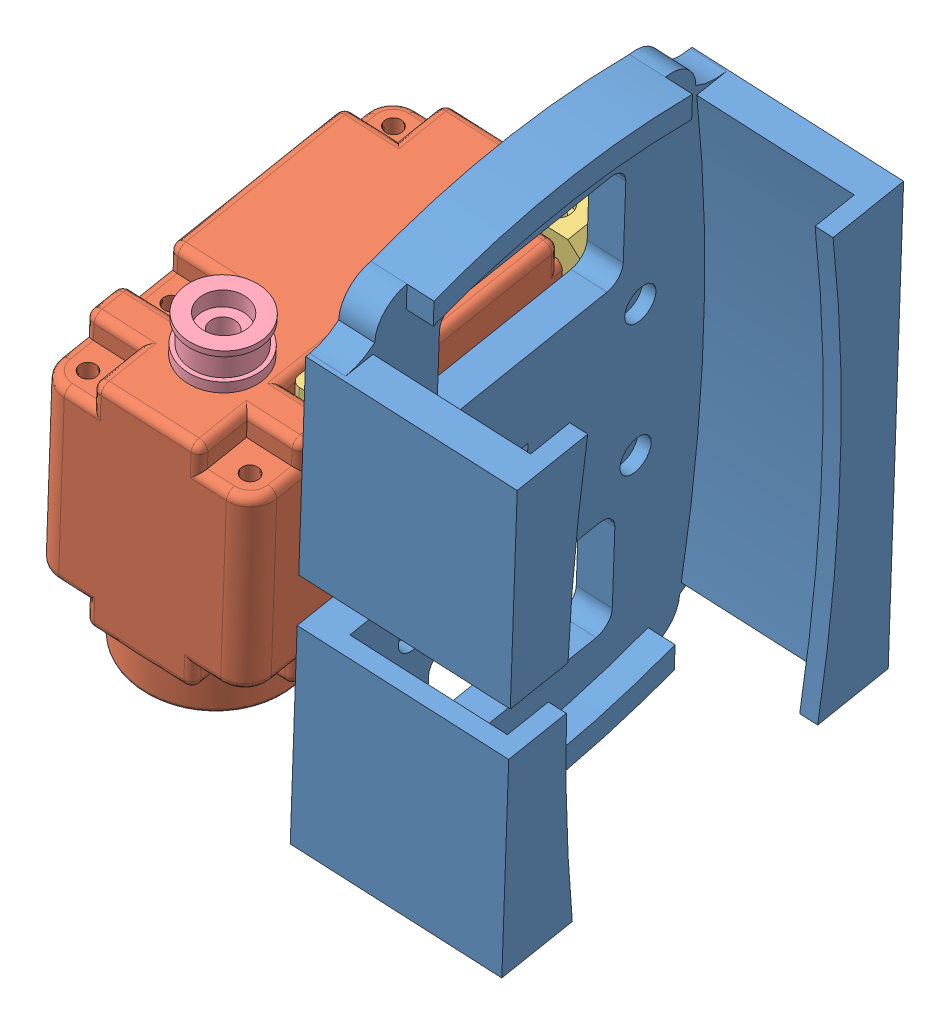
SolidWorks assembly Head, configuration Default. Lengths in mm.
Overall size (59.75 79.66 61.35).
7 component instances, 4 part files, 17 mates.
Components (placement in the parent):
- Cam_holder-1: Cam_holder [Default] at (93.1795 37.2246 30.9254) x (-0.138032 -0.984679 -0.106555) z (0.063253 -0.11613 0.991218) size (71.97 23.5 49.34)
- herkulex_motor-1: herkulex_motor [Default] at (81.1875 52.7673 38.909) x (0.988406 -0.13008 -0.078314) z (-0.063253 0.11613 -0.991218) size (24 34.2 45)
- L joint-1: L joint [Default] at (87.5706 28.2304 13.3816) x (0.138032 0.984679 0.106555) z (0.988406 -0.13008 -0.078314) size (8.2 5.1 8.2)
- L joint-2: L joint [Default] at (91.0679 50.2858 20.8876) x (-0.138032 -0.984679 -0.106555) z (0.988406 -0.13008 -0.078314) size (8.2 5.1 8.2)
- L joint-3: L joint [Default] at (92.858 46.9993 48.939) x (-0.138032 -0.984679 -0.106555) z (0.988406 -0.13008 -0.078314) size (8.2 5.1 8.2)
- L joint-5: L joint [Default] at (89.6832 24.3517 46.4883) x (-0.988406 0.13008 0.078314) z (-0.138032 -0.984679 -0.106555) size (8.2 5.1 8.2)
- support-1: support [Default] at (81.9281 50.7885 51.5433) x (0.138032 0.984679 0.106555) z (-0.106555 -0.092197 0.990023) size (5.5 9 9)
Mates (geometry in assembly coordinates):
- Concentric1: concentric aligned: cylinder of herkulex_motor-1 through (88.8497 53.8611 18.8754) axis (-0.138032 -0.984679 -0.106555) radius 1; cylinder of L joint-1 through (85.04 26.684 15.9345) axis (-0.138032 -0.984679 -0.106555) radius 1.7
- Coincident1: coincident anti-aligned: plane of herkulex_motor-1 through (77.5986 27.1657 36.1385) normal (-0.138032 -0.984679 -0.106555); plane of L joint-1 through (87.8932 27.6382 18.4368) normal (0.138032 0.984679 0.106555)
- Concentric2: concentric aligned: circle of herkulex_motor-1; circle of L joint-2
- Coincident2: coincident anti-aligned: plane of herkulex_motor-1 through (80.7734 49.8133 38.5893) normal (0.138032 0.984679 0.106555); plane of L joint-2 through (90.7453 50.878 15.8324) normal (-0.138032 -0.984679 -0.106555)
- Concentric3: concentric anti-aligned: cylinder of herkulex_motor-1 through (90.6397 50.5747 46.9269) axis (-0.138032 -0.984679 -0.106555) radius 1; cylinder of L joint-3 through (90.4465 49.1961 46.7777) axis (0.138032 0.984679 0.106555) radius 1.7
- Coincident3: coincident anti-aligned: plane of herkulex_motor-1 through (80.7734 49.8133 38.5893) normal (0.138032 0.984679 0.106555); plane of L joint-3 through (92.5354 47.5916 43.8838) normal (-0.138032 -0.984679 -0.106555)
- Concentric5: concentric anti-aligned: cylinder of herkulex_motor-1 through (90.6397 50.5747 46.9269) axis (-0.138032 -0.984679 -0.106555) radius 1; cylinder of L joint-5 through (86.347 19.9511 43.613) axis (0.138032 0.984679 0.106555) radius 1
- Coincident4: coincident anti-aligned: plane of herkulex_motor-1 through (77.5986 27.1657 36.1385) normal (-0.138032 -0.984679 -0.106555); plane of L joint-5 through (89.3606 24.9439 41.4331) normal (0.138032 0.984679 0.106555)
- Parallel1: parallel aligned: plane of herkulex_motor-1 through (63.6244 26.4161 14.2431) normal (-0.063253 0.11613 -0.991218); plane of L joint-1 through (87.5706 28.2304 13.3816) normal (-0.063253 0.11613 -0.991218)
- Parallel2: parallel aligned: plane of herkulex_motor-1 through (63.6244 26.4161 14.2431) normal (-0.063253 0.11613 -0.991218); plane of L joint-2 through (90.7453 50.878 15.8324) normal (-0.063253 0.11613 -0.991218)
- Parallel3: parallel aligned: plane of herkulex_motor-1 through (63.6244 26.4161 14.2431) normal (-0.063253 0.11613 -0.991218); plane of L joint-5 through (89.3606 24.9439 41.4331) normal (-0.063253 0.11613 -0.991218)
- Parallel4: parallel aligned: plane of herkulex_motor-1 through (63.6244 26.4161 14.2431) normal (-0.063253 0.11613 -0.991218); plane of L joint-3 through (92.5354 47.5916 43.8838) normal (-0.063253 0.11613 -0.991218)
- Concentric6: concentric anti-aligned: cylinder of Cam_holder-1 through (87.5963 48.5104 18.3285) axis (0.988406 -0.13008 -0.078314) radius 1; cylinder of L joint-2 through (95.6024 47.4568 17.6942) axis (-0.988406 0.13008 0.078314) radius 1
- Concentric7: concentric anti-aligned: cylinder of Cam_holder-1 through (85.1117 30.7862 16.4105) axis (0.988406 -0.13008 -0.078314) radius 1; cylinder of L joint-1 through (93.1178 29.7326 15.7762) axis (-0.988406 0.13008 0.078314) radius 1
- Coincident9: coincident anti-aligned: plane of Cam_holder-1 through (91.7292 39.6742 8.5523) normal (-0.988406 0.13008 0.078314); plane of L joint-3 through (95.9147 50.1554 43.9686) normal (0.988406 -0.13008 -0.078314)
- Concentric8: concentric aligned: cylinder of herkulex_motor-1 through (80.6168 41.4341 50.531) axis (0.138032 0.984679 0.106555) radius 1.475; circle of support-1
- Coincident10: coincident anti-aligned: plane of herkulex_motor-1 through (81.9281 50.7885 51.5433) normal (0.138032 0.984679 0.106555); plane of support-1 through (81.9281 50.7885 51.5433) normal (-0.138032 -0.984679 -0.106555)
